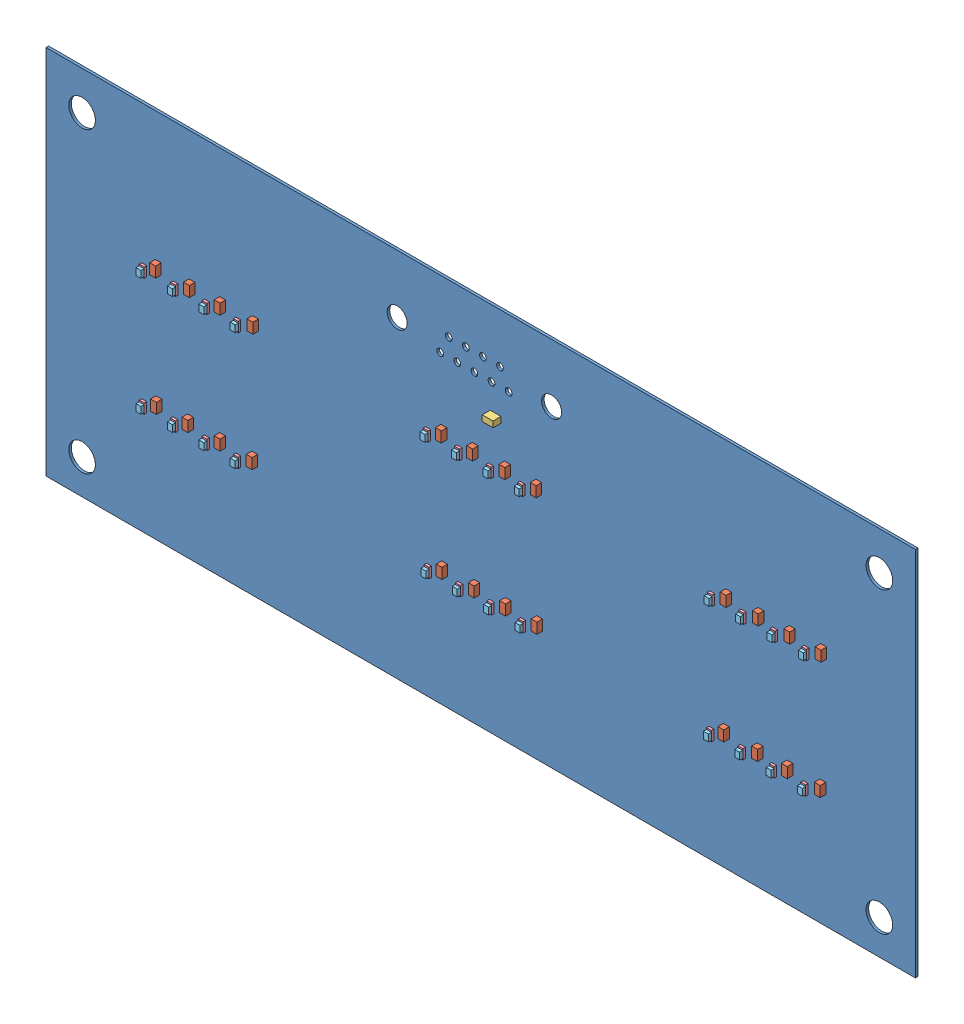
SolidWorks assembly FEV-60_LED_Panel, configuration Default. Lengths in mm.
Overall size (140.72 60.07 1.71).
198 component instances, 5 part files, 0 mates.
Components (placement in the parent):
- FEV-60_LED_Panel.step-1: FEV-60_LED_Panel.step [Default] at origin size (140.72 60.07 1.71)
  - Board.step-1: Board.step [Default] at origin size (140.72 60.07 0.41)
    - Open CASCADE STEP translator 6.8 4.1.1.step-1: Open CASCADE STEP translator 6.8 4.1.1.step [Default] at (0 0 -0.4115) size (140.72 60.07 0.41)
  - R24.step-1: R24.step [Default] at origin size (0.95 1.7 0.9)
    - 6216516608.step-1: 6216516608.step [Default] at (135.509 74.676 0) size (0.95 1.7 0.9)
      - Extruded.step-1: Extruded.step [Default] at origin size (0.95 1.7 0.9)
  - R23.step-1: R23.step [Default] at origin size (0.95 1.7 0.9)
    - 6216516608.step-1: 6216516608.step [Default] at (89.916 74.664 0) size (0.95 1.7 0.9)
      - Extruded.step-1: Extruded.step [Default] at origin size (0.95 1.7 0.9)
  - R22.step-1: R22.step [Default] at origin size (0.95 1.7 0.9)
    - 6216516608.step-1: 6216516608.step [Default] at (43.688 74.676 0) size (0.95 1.7 0.9)
      - Extruded.step-1: Extruded.step [Default] at origin size (0.95 1.7 0.9)
  - R21.step-1: R21.step [Default] at origin size (0.95 1.7 0.9)
    - 6216516608.step-1: 6216516608.step [Default] at (140.97 74.676 0) size (0.95 1.7 0.9)
      - Extruded.step-1: Extruded.step [Default] at origin size (0.95 1.7 0.9)
  - R20.step-1: R20.step [Default] at origin size (0.95 1.7 0.9)
    - 6216516608.step-1: 6216516608.step [Default] at (95.123 74.664 0) size (0.95 1.7 0.9)
      - Extruded.step-1: Extruded.step [Default] at origin size (0.95 1.7 0.9)
  - R19.step-1: R19.step [Default] at origin size (0.95 1.7 0.9)
    - 6216516608.step-1: 6216516608.step [Default] at (48.768 74.676 0) size (0.95 1.7 0.9)
      - Extruded.step-1: Extruded.step [Default] at origin size (0.95 1.7 0.9)
  - R18.step-1: R18.step [Default] at origin size (0.95 1.7 0.9)
    - 6216516608.step-1: 6216516608.step [Default] at (145.796 74.676 0) size (0.95 1.7 0.9)
      - Extruded.step-1: Extruded.step [Default] at origin size (0.95 1.7 0.9)
  - R17.step-1: R17.step [Default] at origin size (0.95 1.7 0.9)
    - 6216516608.step-1: 6216516608.step [Default] at (100.203 74.664 0) size (0.95 1.7 0.9)
      - Extruded.step-1: Extruded.step [Default] at origin size (0.95 1.7 0.9)
  - R16.step-1: R16.step [Default] at origin size (0.95 1.7 0.9)
    - 6216516608.step-1: 6216516608.step [Default] at (53.975 74.676 0) size (0.95 1.7 0.9)
      - Extruded.step-1: Extruded.step [Default] at origin size (0.95 1.7 0.9)
  - R15.step-1: R15.step [Default] at origin size (0.95 1.7 0.9)
    - 6216516608.step-1: 6216516608.step [Default] at (151.13 74.688 0) size (0.95 1.7 0.9)
      - Extruded.step-1: Extruded.step [Default] at origin size (0.95 1.7 0.9)
  - R14.step-1: R14.step [Default] at origin size (0.95 1.7 0.9)
    - 6216516608.step-1: 6216516608.step [Default] at (105.283 74.664 0) size (0.95 1.7 0.9)
      - Extruded.step-1: Extruded.step [Default] at origin size (0.95 1.7 0.9)
  - R13.step-1: R13.step [Default] at origin size (0.95 1.7 0.9)
    - 6216516608.step-1: 6216516608.step [Default] at (59.182 74.676 0) size (0.95 1.7 0.9)
      - Extruded.step-1: Extruded.step [Default] at origin size (0.95 1.7 0.9)
  - R12.step-1: R12.step [Default] at origin size (0.95 1.7 0.9)
    - 6216516608.step-1: 6216516608.step [Default] at (135.89 93.726 0) size (0.95 1.7 0.9)
      - Extruded.step-1: Extruded.step [Default] at origin size (0.95 1.7 0.9)
  - R11.step-1: R11.step [Default] at origin size (0.95 1.7 0.9)
    - 6216516608.step-1: 6216516608.step [Default] at (89.789 93.726 0) size (0.95 1.7 0.9)
      - Extruded.step-1: Extruded.step [Default] at origin size (0.95 1.7 0.9)
  - R10.step-1: R10.step [Default] at origin size (0.95 1.7 0.9)
    - 6216516608.step-1: 6216516608.step [Default] at (43.561 93.726 0) size (0.95 1.7 0.9)
      - Extruded.step-1: Extruded.step [Default] at origin size (0.95 1.7 0.9)
  - R9.step-1: R9.step [Default] at origin size (0.95 1.7 0.9)
    - 6216516608.step-1: 6216516608.step [Default] at (141.097 93.726 0) size (0.95 1.7 0.9)
      - Extruded.step-1: Extruded.step [Default] at origin size (0.95 1.7 0.9)
  - R8.step-1: R8.step [Default] at origin size (0.95 1.7 0.9)
    - 6216516608.step-1: 6216516608.step [Default] at (94.869 93.726 0) size (0.95 1.7 0.9)
      - Extruded.step-1: Extruded.step [Default] at origin size (0.95 1.7 0.9)
  - R7.step-1: R7.step [Default] at origin size (0.95 1.7 0.9)
    - 6216516608.step-1: 6216516608.step [Default] at (49.022 93.726 0) size (0.95 1.7 0.9)
      - Extruded.step-1: Extruded.step [Default] at origin size (0.95 1.7 0.9)
  - R6.step-1: R6.step [Default] at origin size (0.95 1.7 0.9)
    - 6216516608.step-1: 6216516608.step [Default] at (146.177 93.726 0) size (0.95 1.7 0.9)
      - Extruded.step-1: Extruded.step [Default] at origin size (0.95 1.7 0.9)
  - R5.step-1: R5.step [Default] at origin size (0.95 1.7 0.9)
    - 6216516608.step-1: 6216516608.step [Default] at (100.076 93.726 0) size (0.95 1.7 0.9)
      - Extruded.step-1: Extruded.step [Default] at origin size (0.95 1.7 0.9)
  - R4.step-1: R4.step [Default] at origin size (0.95 1.7 0.9)
    - 6216516608.step-1: 6216516608.step [Default] at (53.975 93.726 0) size (0.95 1.7 0.9)
      - Extruded.step-1: Extruded.step [Default] at origin size (0.95 1.7 0.9)
  - R3.step-1: R3.step [Default] at origin size (0.95 1.7 0.9)
    - 6216516608.step-1: 6216516608.step [Default] at (151.257 93.726 0) size (0.95 1.7 0.9)
      - Extruded.step-1: Extruded.step [Default] at origin size (0.95 1.7 0.9)
  - R2.step-1: R2.step [Default] at origin size (0.95 1.7 0.9)
    - 6216516608.step-1: 6216516608.step [Default] at (105.156 93.726 0) size (0.95 1.7 0.9)
      - Extruded.step-1: Extruded.step [Default] at origin size (0.95 1.7 0.9)
  - C1.step-1: C1.step [Default] at origin size (1.75 0.95 1.3)
    - 6216520128.step-1: 6216520128.step [Default] at (98.171 100.076 0) size (1.75 0.95 1.3)
      - Extruded-0.step-1: Extruded-0.step [Default] at origin size (1.75 0.95 1.3)
  - R1.step-1: R1.step [Default] at origin size (0.95 1.7 0.9)
    - 6216516608.step-1: 6216516608.step [Default] at (59.309 93.726 0) size (0.95 1.7 0.9)
      - Extruded.step-1: Extruded.step [Default] at origin size (0.95 1.7 0.9)
  - DS24.step-1: DS24.step [Default] at origin size (0.8 1.6 0.9)
    - 6363329008.step-1: 6363329008.step [Default] at (133.0958 73.1522 0) size (0.8 1.6 0.4)
      - Extruded-1.step-1: Extruded-1.step [Default] at origin size (0.8 1.6 0.4)
    - 6363328768.step-1: 6363328768.step [Default] at (133.0958 73.1522 0.4) size (0.8 1.1 0.5)
      - Extruded-2.step-1: Extruded-2.step [Default] at origin size (0.8 1.1 0.5)
  - DS23.step-1: DS23.step [Default] at origin size (0.8 1.6 0.9)
    - 6363329008.step-1: 6363329008.step [Default] at (87.3759 73.1521 0) size (0.8 1.6 0.4)
      - Extruded-1.step-1: Extruded-1.step [Default] at origin size (0.8 1.6 0.4)
    - 6363328768.step-1: 6363328768.step [Default] at (87.3759 73.1521 0.4) size (0.8 1.1 0.5)
      - Extruded-2.step-1: Extruded-2.step [Default] at origin size (0.8 1.1 0.5)
  - DS22.step-1: DS22.step [Default] at origin size (0.8 1.6 0.9)
    - 6363329008.step-1: 6363329008.step [Default] at (41.2749 73.1521 0) size (0.8 1.6 0.4)
      - Extruded-1.step-1: Extruded-1.step [Default] at origin size (0.8 1.6 0.4)
    - 6363328768.step-1: 6363328768.step [Default] at (41.2749 73.1521 0.4) size (0.8 1.1 0.5)
      - Extruded-2.step-1: Extruded-2.step [Default] at origin size (0.8 1.1 0.5)
  - DS21.step-1: DS21.step [Default] at origin size (0.8 1.6 0.9)
    - 6363329008.step-1: 6363329008.step [Default] at (138.1758 73.1522 0) size (0.8 1.6 0.4)
      - Extruded-1.step-1: Extruded-1.step [Default] at origin size (0.8 1.6 0.4)
    - 6363328768.step-1: 6363328768.step [Default] at (138.1758 73.1522 0.4) size (0.8 1.1 0.5)
      - Extruded-2.step-1: Extruded-2.step [Default] at origin size (0.8 1.1 0.5)
  - DS20.step-1: DS20.step [Default] at origin size (0.8 1.6 0.9)
    - 6363329008.step-1: 6363329008.step [Default] at (92.4559 73.1521 0) size (0.8 1.6 0.4)
      - Extruded-1.step-1: Extruded-1.step [Default] at origin size (0.8 1.6 0.4)
    - 6363328768.step-1: 6363328768.step [Default] at (92.4559 73.1521 0.4) size (0.8 1.1 0.5)
      - Extruded-2.step-1: Extruded-2.step [Default] at origin size (0.8 1.1 0.5)
  - DS19.step-1: DS19.step [Default] at origin size (0.8 1.6 0.9)
    - 6363329008.step-1: 6363329008.step [Default] at (46.3549 73.1521 0) size (0.8 1.6 0.4)
      - Extruded-1.step-1: Extruded-1.step [Default] at origin size (0.8 1.6 0.4)
    - 6363328768.step-1: 6363328768.step [Default] at (46.3549 73.1521 0.4) size (0.8 1.1 0.5)
      - Extruded-2.step-1: Extruded-2.step [Default] at origin size (0.8 1.1 0.5)
  - DS18.step-1: DS18.step [Default] at origin size (0.8 1.6 0.9)
    - 6363329008.step-1: 6363329008.step [Default] at (143.2558 73.1522 0) size (0.8 1.6 0.4)
      - Extruded-1.step-1: Extruded-1.step [Default] at origin size (0.8 1.6 0.4)
    - 6363328768.step-1: 6363328768.step [Default] at (143.2558 73.1522 0.4) size (0.8 1.1 0.5)
      - Extruded-2.step-1: Extruded-2.step [Default] at origin size (0.8 1.1 0.5)
  - DS17.step-1: DS17.step [Default] at origin size (0.8 1.6 0.9)
    - 6363329008.step-1: 6363329008.step [Default] at (97.5359 73.1521 0) size (0.8 1.6 0.4)
      - Extruded-1.step-1: Extruded-1.step [Default] at origin size (0.8 1.6 0.4)
    - 6363328768.step-1: 6363328768.step [Default] at (97.5359 73.1521 0.4) size (0.8 1.1 0.5)
      - Extruded-2.step-1: Extruded-2.step [Default] at origin size (0.8 1.1 0.5)
  - DS16.step-1: DS16.step [Default] at origin size (0.8 1.6 0.9)
    - 6363329008.step-1: 6363329008.step [Default] at (51.4349 73.1521 0) size (0.8 1.6 0.4)
      - Extruded-1.step-1: Extruded-1.step [Default] at origin size (0.8 1.6 0.4)
    - 6363328768.step-1: 6363328768.step [Default] at (51.4349 73.1521 0.4) size (0.8 1.1 0.5)
      - Extruded-2.step-1: Extruded-2.step [Default] at origin size (0.8 1.1 0.5)
  - DS15.step-1: DS15.step [Default] at origin size (0.8 1.6 0.9)
    - 6363329008.step-1: 6363329008.step [Default] at (148.3358 73.1522 0) size (0.8 1.6 0.4)
      - Extruded-1.step-1: Extruded-1.step [Default] at origin size (0.8 1.6 0.4)
    - 6363328768.step-1: 6363328768.step [Default] at (148.3358 73.1522 0.4) size (0.8 1.1 0.5)
      - Extruded-2.step-1: Extruded-2.step [Default] at origin size (0.8 1.1 0.5)
  - DS14.step-1: DS14.step [Default] at origin size (0.8 1.6 0.9)
    - 6363329008.step-1: 6363329008.step [Default] at (102.6159 73.1521 0) size (0.8 1.6 0.4)
      - Extruded-1.step-1: Extruded-1.step [Default] at origin size (0.8 1.6 0.4)
    - 6363328768.step-1: 6363328768.step [Default] at (102.6159 73.1521 0.4) size (0.8 1.1 0.5)
      - Extruded-2.step-1: Extruded-2.step [Default] at origin size (0.8 1.1 0.5)
  - DS13.step-1: DS13.step [Default] at origin size (0.8 1.6 0.9)
    - 6363329008.step-1: 6363329008.step [Default] at (56.5149 73.1521 0) size (0.8 1.6 0.4)
      - Extruded-1.step-1: Extruded-1.step [Default] at origin size (0.8 1.6 0.4)
    - 6363328768.step-1: 6363328768.step [Default] at (56.5149 73.1521 0.4) size (0.8 1.1 0.5)
      - Extruded-2.step-1: Extruded-2.step [Default] at origin size (0.8 1.1 0.5)
  - DS12.step-1: DS12.step [Default] at origin size (0.8 1.6 0.9)
    - 6363329008.step-1: 6363329008.step [Default] at (133.2228 92.2022 0) size (0.8 1.6 0.4)
      - Extruded-1.step-1: Extruded-1.step [Default] at origin size (0.8 1.6 0.4)
    - 6363328768.step-1: 6363328768.step [Default] at (133.2228 92.2022 0.4) size (0.8 1.1 0.5)
      - Extruded-2.step-1: Extruded-2.step [Default] at origin size (0.8 1.1 0.5)
  - DS11.step-1: DS11.step [Default] at origin size (0.8 1.6 0.9)
    - 6363329008.step-1: 6363329008.step [Default] at (87.249 92.214 0) size (0.8 1.6 0.4)
      - Extruded-1.step-1: Extruded-1.step [Default] at origin size (0.8 1.6 0.4)
    - 6363328768.step-1: 6363328768.step [Default] at (87.249 92.214 0.4) size (0.8 1.1 0.5)
      - Extruded-2.step-1: Extruded-2.step [Default] at origin size (0.8 1.1 0.5)
  - DS10.step-1: DS10.step [Default] at origin size (0.8 1.6 0.9)
    - 6363329008.step-1: 6363329008.step [Default] at (41.275 92.214 0) size (0.8 1.6 0.4)
      - Extruded-1.step-1: Extruded-1.step [Default] at origin size (0.8 1.6 0.4)
    - 6363328768.step-1: 6363328768.step [Default] at (41.275 92.214 0.4) size (0.8 1.1 0.5)
      - Extruded-2.step-1: Extruded-2.step [Default] at origin size (0.8 1.1 0.5)
  - DS9.step-1: DS9.step [Default] at origin size (0.8 1.6 0.9)
    - 6363329008.step-1: 6363329008.step [Default] at (138.3028 92.2022 0) size (0.8 1.6 0.4)
      - Extruded-1.step-1: Extruded-1.step [Default] at origin size (0.8 1.6 0.4)
    - 6363328768.step-1: 6363328768.step [Default] at (138.3028 92.2022 0.4) size (0.8 1.1 0.5)
      - Extruded-2.step-1: Extruded-2.step [Default] at origin size (0.8 1.1 0.5)
  - DS8.step-1: DS8.step [Default] at origin size (0.8 1.6 0.9)
    - 6363329008.step-1: 6363329008.step [Default] at (92.3289 92.2021 0) size (0.8 1.6 0.4)
      - Extruded-1.step-1: Extruded-1.step [Default] at origin size (0.8 1.6 0.4)
    - 6363328768.step-1: 6363328768.step [Default] at (92.3289 92.2021 0.4) size (0.8 1.1 0.5)
      - Extruded-2.step-1: Extruded-2.step [Default] at origin size (0.8 1.1 0.5)
  - DS7.step-1: DS7.step [Default] at origin size (0.8 1.6 0.9)
    - 6363329008.step-1: 6363329008.step [Default] at (46.3549 92.2021 0) size (0.8 1.6 0.4)
      - Extruded-1.step-1: Extruded-1.step [Default] at origin size (0.8 1.6 0.4)
    - 6363328768.step-1: 6363328768.step [Default] at (46.3549 92.2021 0.4) size (0.8 1.1 0.5)
      - Extruded-2.step-1: Extruded-2.step [Default] at origin size (0.8 1.1 0.5)
  - DS6.step-1: DS6.step [Default] at origin size (0.8 1.6 0.9)
    - 6363329008.step-1: 6363329008.step [Default] at (143.3828 92.2022 0) size (0.8 1.6 0.4)
      - Extruded-1.step-1: Extruded-1.step [Default] at origin size (0.8 1.6 0.4)
    - 6363328768.step-1: 6363328768.step [Default] at (143.3828 92.2022 0.4) size (0.8 1.1 0.5)
      - Extruded-2.step-1: Extruded-2.step [Default] at origin size (0.8 1.1 0.5)
  - DS5.step-1: DS5.step [Default] at origin size (0.8 1.6 0.9)
    - 6363329008.step-1: 6363329008.step [Default] at (97.4089 92.2021 0) size (0.8 1.6 0.4)
      - Extruded-1.step-1: Extruded-1.step [Default] at origin size (0.8 1.6 0.4)
    - 6363328768.step-1: 6363328768.step [Default] at (97.4089 92.2021 0.4) size (0.8 1.1 0.5)
      - Extruded-2.step-1: Extruded-2.step [Default] at origin size (0.8 1.1 0.5)
  - DS4.step-1: DS4.step [Default] at origin size (0.8 1.6 0.9)
    - 6363329008.step-1: 6363329008.step [Default] at (51.4349 92.2021 0) size (0.8 1.6 0.4)
      - Extruded-1.step-1: Extruded-1.step [Default] at origin size (0.8 1.6 0.4)
    - 6363328768.step-1: 6363328768.step [Default] at (51.4349 92.2021 0.4) size (0.8 1.1 0.5)
      - Extruded-2.step-1: Extruded-2.step [Default] at origin size (0.8 1.1 0.5)
  - DS3.step-1: DS3.step [Default] at origin size (0.8 1.6 0.9)
    - 6363329008.step-1: 6363329008.step [Default] at (148.4628 92.2022 0) size (0.8 1.6 0.4)
      - Extruded-1.step-1: Extruded-1.step [Default] at origin size (0.8 1.6 0.4)
    - 6363328768.step-1: 6363328768.step [Default] at (148.4628 92.2022 0.4) size (0.8 1.1 0.5)
      - Extruded-2.step-1: Extruded-2.step [Default] at origin size (0.8 1.1 0.5)
  - DS2.step-1: DS2.step [Default] at origin size (0.8 1.6 0.9)
    - 6363329008.step-1: 6363329008.step [Default] at (102.4889 92.2021 0) size (0.8 1.6 0.4)
      - Extruded-1.step-1: Extruded-1.step [Default] at origin size (0.8 1.6 0.4)
    - 6363328768.step-1: 6363328768.step [Default] at (102.4889 92.2021 0.4) size (0.8 1.1 0.5)
      - Extruded-2.step-1: Extruded-2.step [Default] at origin size (0.8 1.1 0.5)
  - DS1.step-1: DS1.step [Default] at origin size (0.8 1.6 0.9)
    - 6363329008.step-1: 6363329008.step [Default] at (56.5149 92.2021 0) size (0.8 1.6 0.4)
      - Extruded-1.step-1: Extruded-1.step [Default] at origin size (0.8 1.6 0.4)
    - 6363328768.step-1: 6363328768.step [Default] at (56.5149 92.2021 0.4) size (0.8 1.1 0.5)
      - Extruded-2.step-1: Extruded-2.step [Default] at origin size (0.8 1.1 0.5)
